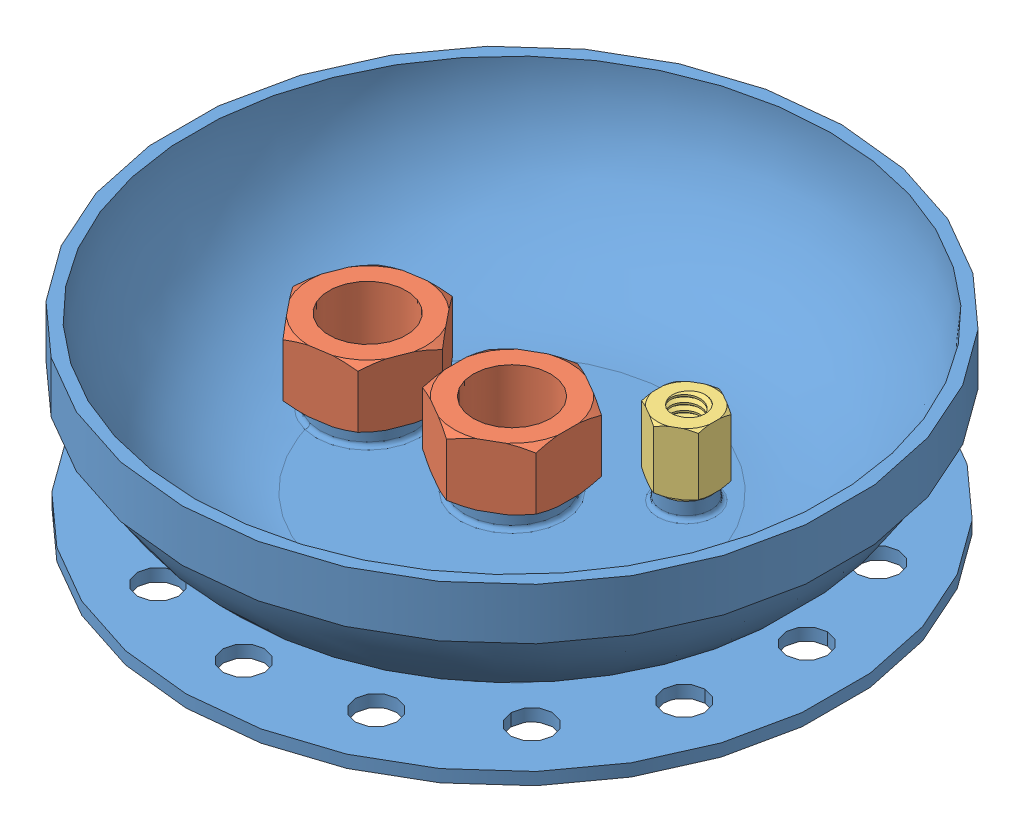
SolidWorks assembly Assem1, configuration Default. Lengths in mm.
Overall size (203.2 54.61 203.2).
4 component instances, 3 part files, 3 mates.
Components (placement in the parent):
- Tank Connector Ver 3-Fuelside-1: Tank Connector Ver 3-Fuelside [v001_MatArnold] at (82.4604 78.7011 155.0968) size (203.2 54.61 203.2)
- -12 AN tank fitting-1: -12 AN tank fitting [Default] at (82.4604 98.3861 155.0968) size (34.92 20.32 40.33)
- -4 AN tank fitting High Press-1: -4 AN tank fitting High Press [Default] at (111.6467 98.3861 130.6065) size (17.48 21.11 20.18)
- -12 AN tank fitting-2: -12 AN tank fitting [Default] at (38.0104 98.3861 155.0968) x (0.932938 0 0.360038) z (-0.360038 0 0.932938) size (34.92 20.32 40.33)
Mates (geometry in assembly coordinates):
- Coincident1: coincident aligned: circle of Tank Connector Ver 3-Fuelside-1; circle of -12 AN tank fitting-2
- Coincident3: coincident aligned: circle of Tank Connector Ver 3-Fuelside-1; circle of -12 AN tank fitting-1
- Coincident4: coincident aligned: circle of Tank Connector Ver 3-Fuelside-1; circle of -4 AN tank fitting High Press-1
